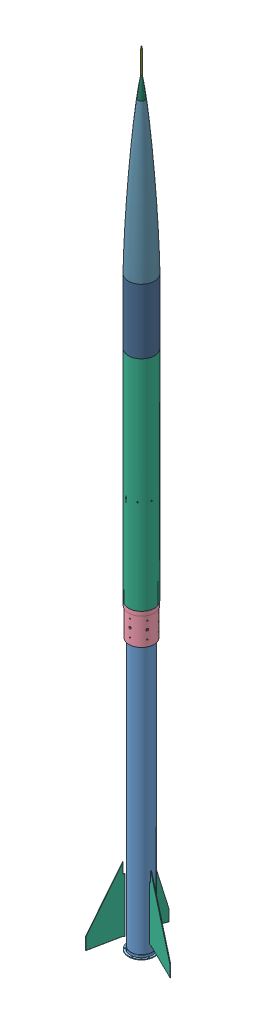
SolidWorks assembly NFPA_fullAssembly, configuration Default. Lengths in mm.
Overall size (305.82 3606.47 308.87).
264 component instances, 51 part files, 9 mates.
Components (placement in the parent):
- MotorAssembly-1: MotorAssembly [Default] at origin size (305.82 1521.25 308.87)
  - NFPAMotor-1: NFPAMotor [Default] at origin size (101.6 1308.35 101.6)
  - NFPA_ThrustPlate_MotorTube_V1-1: NFPA_ThrustPlate_MotorTube_V1 [Default] at (0 1295.654 0) x (0 1 0) z (-0.603474 0 0.797383) size (12 104.3 104.3)
  - 3014T471_STEEL EYEBOLT WITH SHOULDER - FOR LIFTING-1: 3014T471_STEEL EYEBOLT WITH SHOULDER - FOR LIFTING [3014T471] at (0 1337.9759 0) x (0.928789 0 0.37061) z (-0.37061 0 0.928789) size (42.07 88.72 17.46)
  - NFPA_MotorCoupler_MotorTube_V1-1: NFPA_MotorCoupler_MotorTube_V1 [Default] at (0 1231.454 0) x (0 -1 0) z (0.997437 0 -0.071547) size (273.05 119.3 119.3)
  - NFPA_CarbonTube_MotorTube_V1-1: NFPA_CarbonTube_MotorTube_V1 [Default] at (0 -10.7 0) x (0.97056 0 0.24086) z (-0.24086 0 0.97056) size (121.7 1369.15 121.7) (hidden)
  - NFPA_LowerRetainingStructure_MotorTube_V1-1: NFPA_LowerRetainingStructure_MotorTube_V1 [Default] at (0 -13.875 0) x (0.980838 0 -0.194827) z (0.194827 0 0.980838) size (118.62 3.17 118.62)
  - Fins-1: Fins [Default] at (1.2008 2699.2539 -1.2506) x (-0.276689 0 -0.96096) z (-0.96096 0 0.276689) size (128.37 356.05 3)
  - Fins-2: Fins [Default] at (-1.6835 2699.2539 -0.4147) x (-0.693871 0 0.7201) z (0.7201 0 0.693871) size (128.37 356.05 3)
  - Fins-3: Fins [Default] at (0.4826 2699.2539 1.6653) x (0.97056 0 0.24086) z (0.24086 0 -0.97056) size (128.37 356.05 3)
- NFPA_ASMPlusTube_AvionicsBay_V1-1: NFPA_ASMPlusTube_AvionicsBay_V1 [Default] at (4.3626 1788.1446 -124.7024) x (0.97858 0 0.205865) z (-0.205865 0 0.97858) size (169.53 1134.65 169.53)
  - NFPA_FinalAssembly_AvionicsBay_V1-1: NFPA_FinalAssembly_AvionicsBay_V1 [Default] at origin size (124.5 527 114.3)
    - NFPA_BottomBulkhead_AvionicsBay_V1-1: NFPA_BottomBulkhead_AvionicsBay_V1 [Default] at (21.4027 17.8594 122.9295) size (114.3 13 114.3)
    - NFPA_ThreadedRod_AvionicsBay_V1-1: NFPA_ThreadedRod_AvionicsBay_V1 [Default] at (-4.7602 2.8594 149.0924) size (6.35 475 6.35)
    - NFPA_ThreadedRod_AvionicsBay_V1-2: NFPA_ThreadedRod_AvionicsBay_V1 [Default] at (47.5656 2.8594 149.0924) size (6.35 475 6.35)
    - NFPA_ThreadedRod_AvionicsBay_V1-3: NFPA_ThreadedRod_AvionicsBay_V1 [Default] at (47.5656 2.8594 96.7664) size (6.35 475 6.35)
    - NFPA_ThreadedRod_AvionicsBay_V1-4: NFPA_ThreadedRod_AvionicsBay_V1 [Default] at (-4.7602 2.8594 96.7664) size (6.35 475 6.35)
    - 90107A029_TYPE 316 STAINLESS STEEL FLAT WASHER-1: 90107A029_TYPE 316 STAINLESS STEEL FLAT WASHER [90107A029] at (-4.7602 17.8594 96.7664) x (-0.837169 0 -0.546944) z (-0.546944 0 0.837169) size (15.88 1.09 15.88)
    - 90107A029_TYPE 316 STAINLESS STEEL FLAT WASHER-2: 90107A029_TYPE 316 STAINLESS STEEL FLAT WASHER [90107A029] at (-4.7602 17.8594 149.0924) x (-0.837169 0 -0.546944) z (-0.546944 0 0.837169) size (15.88 1.09 15.88)
    - 90107A029_TYPE 316 STAINLESS STEEL FLAT WASHER-3: 90107A029_TYPE 316 STAINLESS STEEL FLAT WASHER [90107A029] at (47.5656 17.8594 96.7664) x (-0.837169 0 -0.546944) z (-0.546944 0 0.837169) size (15.88 1.09 15.88)
    - 90107A029_TYPE 316 STAINLESS STEEL FLAT WASHER-4: 90107A029_TYPE 316 STAINLESS STEEL FLAT WASHER [90107A029] at (47.5656 17.8594 149.0924) x (-0.837169 0 -0.546944) z (-0.546944 0 0.837169) size (15.88 1.09 15.88)
    - 95462A029_GRADE 5 STEEL HEX NUT-1: 95462A029_GRADE 5 STEEL HEX NUT [95462A029] at (-4.7602 13.9891 149.0924) x (1 0 0) z (0 1 0) size (11.11 12.83 7.14)
    - 95462A029_GRADE 5 STEEL HEX NUT-2: 95462A029_GRADE 5 STEEL HEX NUT [95462A029] at (-4.7602 13.9891 96.7664) x (1 0 0) z (0 1 0) size (11.11 12.83 7.14)
    - 95462A029_GRADE 5 STEEL HEX NUT-3: 95462A029_GRADE 5 STEEL HEX NUT [95462A029] at (47.5656 13.9891 96.7664) x (1 0 0) z (0 1 0) size (11.11 12.83 7.14)
    - 95462A029_GRADE 5 STEEL HEX NUT-4: 95462A029_GRADE 5 STEEL HEX NUT [95462A029] at (47.5656 13.9891 149.0924) x (1 0 0) z (0 1 0) size (11.11 12.83 7.14)
    - NFPA_Raptor_AvionicsBay_V1-1: NFPA_Raptor_AvionicsBay_V1 [Default] at (51.4027 -12.9702 122.6596) x (0 1 0) z (-0.700909 0 0.71325) size (152.4 44.2 44.2)
    - 90107A029_TYPE 316 STAINLESS STEEL FLAT WASHER-5: 90107A029_TYPE 316 STAINLESS STEEL FLAT WASHER [90107A029] at (47.5656 56.1811 149.0924) x (-0.837169 0 -0.546944) z (-0.546944 0 0.837169) size (15.88 1.09 15.88)
    - 90107A029_TYPE 316 STAINLESS STEEL FLAT WASHER-6: 90107A029_TYPE 316 STAINLESS STEEL FLAT WASHER [90107A029] at (-4.7602 56.4993 149.0924) x (-0.797616 0 -0.603165) z (-0.603165 0 0.797616) size (15.88 1.09 15.88)
    - 90107A029_TYPE 316 STAINLESS STEEL FLAT WASHER-7: 90107A029_TYPE 316 STAINLESS STEEL FLAT WASHER [90107A029] at (47.5656 58.7462 149.0924) x (-0.771468 0 -0.636268) z (-0.636268 0 0.771468) size (15.88 1.09 15.88)
    - 90107A029_TYPE 316 STAINLESS STEEL FLAT WASHER-8: 90107A029_TYPE 316 STAINLESS STEEL FLAT WASHER [90107A029] at (-4.7602 59.0072 149.0924) x (-0.839969 0 -0.542635) z (-0.542635 0 0.839969) size (15.88 1.09 15.88)
    - 90107A029_TYPE 316 STAINLESS STEEL FLAT WASHER-9: 90107A029_TYPE 316 STAINLESS STEEL FLAT WASHER [90107A029] at (47.5656 58.8468 96.7664) x (-0.837169 0 -0.546944) z (-0.546944 0 0.837169) size (15.88 1.09 15.88)
    - 90107A029_TYPE 316 STAINLESS STEEL FLAT WASHER-10: 90107A029_TYPE 316 STAINLESS STEEL FLAT WASHER [90107A029] at (-4.7602 58.9433 96.7664) x (-0.782663 0 -0.622446) z (-0.622446 0 0.782663) size (15.88 1.09 15.88)
    - 90107A029_TYPE 316 STAINLESS STEEL FLAT WASHER-11: 90107A029_TYPE 316 STAINLESS STEEL FLAT WASHER [90107A029] at (-4.7602 56.1457 96.7664) x (-0.837169 0 -0.546944) z (-0.546944 0 0.837169) size (15.88 1.09 15.88)
    - 90107A029_TYPE 316 STAINLESS STEEL FLAT WASHER-12: 90107A029_TYPE 316 STAINLESS STEEL FLAT WASHER [90107A029] at (47.5656 56.204 96.7664) x (-0.837169 0 -0.546944) z (-0.546944 0 0.837169) size (15.88 1.09 15.88)
    - 95462A029_GRADE 5 STEEL HEX NUT-5: 95462A029_GRADE 5 STEEL HEX NUT [95462A029] at (-4.7602 52.2753 96.7664) x (0.99903 0 0.044034) z (0 -1 0) size (11.11 12.83 7.14)
    - 95462A029_GRADE 5 STEEL HEX NUT-6: 95462A029_GRADE 5 STEEL HEX NUT [95462A029] at (47.5656 52.3337 96.7664) x (0.997972 0 0.063657) z (0 1 0) size (11.11 12.83 7.14)
    - 95462A029_GRADE 5 STEEL HEX NUT-7: 95462A029_GRADE 5 STEEL HEX NUT [95462A029] at (47.5656 61.6249 96.7664) x (0.988116 0 -0.153711) z (0 1 0) size (11.11 12.83 7.14)
    - 95462A029_GRADE 5 STEEL HEX NUT-8: 95462A029_GRADE 5 STEEL HEX NUT [95462A029] at (-4.7602 61.7214 96.7664) x (1 0 0) z (0 1 0) size (11.11 12.83 7.14)
    - 95462A029_GRADE 5 STEEL HEX NUT-9: 95462A029_GRADE 5 STEEL HEX NUT [95462A029] at (47.5656 61.5243 149.0924) x (1 0 0) z (0 1 0) size (11.11 12.83 7.14)
    - 95462A029_GRADE 5 STEEL HEX NUT-10: 95462A029_GRADE 5 STEEL HEX NUT [95462A029] at (-4.7602 61.7853 149.0924) x (0.99999 0 -0.004368) z (0 1 0) size (11.11 12.83 7.14)
    - 95462A029_GRADE 5 STEEL HEX NUT-11: 95462A029_GRADE 5 STEEL HEX NUT [95462A029] at (-4.7602 52.629 149.0924) x (1 0 0) z (0 -1 0) size (11.11 12.83 7.14)
    - 95462A029_GRADE 5 STEEL HEX NUT-12: 95462A029_GRADE 5 STEEL HEX NUT [95462A029] at (47.5656 52.3108 149.0924) x (0.985546 0 -0.169407) z (0 -1 0) size (11.11 12.83 7.14)
    - NFPA_TopBulkhead_AvionicsBay_V1-1: NFPA_TopBulkhead_AvionicsBay_V1 [Default] at (21.4027 430.8586 122.9293) x (-1 0 0) z (0 0 -1) size (114.3 13 114.3)
    - 90107A029_TYPE 316 STAINLESS STEEL FLAT WASHER-13: 90107A029_TYPE 316 STAINLESS STEEL FLAT WASHER [90107A029] at (-4.7602 444.9508 149.0924) x (-0.837169 0 -0.546944) z (-0.546944 0 0.837169) size (15.88 1.09 15.88)
    - 90107A029_TYPE 316 STAINLESS STEEL FLAT WASHER-14: 90107A029_TYPE 316 STAINLESS STEEL FLAT WASHER [90107A029] at (47.5656 444.9508 149.0924) x (-0.837169 0 -0.546944) z (-0.546944 0 0.837169) size (15.88 1.09 15.88)
    - 90107A029_TYPE 316 STAINLESS STEEL FLAT WASHER-15: 90107A029_TYPE 316 STAINLESS STEEL FLAT WASHER [90107A029] at (-4.7602 444.9508 96.7664) x (-0.837169 0 -0.546944) z (-0.546944 0 0.837169) size (15.88 1.09 15.88)
    - 90107A029_TYPE 316 STAINLESS STEEL FLAT WASHER-16: 90107A029_TYPE 316 STAINLESS STEEL FLAT WASHER [90107A029] at (47.5656 444.9508 96.7664) x (-0.837169 0 -0.546944) z (-0.546944 0 0.837169) size (15.88 1.09 15.88)
    - 95462A029_GRADE 5 STEEL HEX NUT-13: 95462A029_GRADE 5 STEEL HEX NUT [95462A029] at (47.5656 447.7289 149.0924) x (1 0 0) z (0 1 0) size (11.11 12.83 7.14)
    - 95462A029_GRADE 5 STEEL HEX NUT-14: 95462A029_GRADE 5 STEEL HEX NUT [95462A029] at (-4.7602 447.7289 149.0924) x (1 0 0) z (0 1 0) size (11.11 12.83 7.14)
    - 95462A029_GRADE 5 STEEL HEX NUT-15: 95462A029_GRADE 5 STEEL HEX NUT [95462A029] at (-4.7602 447.7289 96.7664) x (1 0 0) z (0 -1 0) size (11.11 12.83 7.14)
    - 95462A029_GRADE 5 STEEL HEX NUT-16: 95462A029_GRADE 5 STEEL HEX NUT [95462A029] at (47.5656 447.7289 96.7664) x (1 0 0) z (0 -1 0) size (11.11 12.83 7.14)
    - NFPA_Raptor_AvionicsBay_V1-2: NFPA_Raptor_AvionicsBay_V1 [Default] at (-10.5973 474.6883 122.9293) x (0 -1 0) z (0.694658 0 0.71934) size (152.4 44.2 44.2)
    - NFPA_GeneralPCB_AvionicsBay_V1-2: NFPA_GeneralPCB_AvionicsBay_V1 [Default] at (21.4026 125.3758 122.9294) x (1 0 -0.000004) z (0.000004 0 1) size (75 1.6 75)
    - NFPA_GeneralPCB_AvionicsBay_V1-3: NFPA_GeneralPCB_AvionicsBay_V1 [Default] at (21.4025 146.9758 122.9295) size (75 1.6 75)
    - NFPA_GeneralPCB_AvionicsBay_V1-4: NFPA_GeneralPCB_AvionicsBay_V1 [Default] at (21.4027 168.5758 122.9295) size (75 1.6 75)
    - NFPA_GeneralPCB_AvionicsBay_V1-5: NFPA_GeneralPCB_AvionicsBay_V1 [Default] at (21.4027 211.7758 122.9295) size (75 1.6 75)
    - NFPA_GeneralPCB_AvionicsBay_V1-6: NFPA_GeneralPCB_AvionicsBay_V1 [Default] at (21.4025 190.1758 122.9295) size (75 1.6 75)
    - NFPA_GeneralPCB_AvionicsBay_V1-7: NFPA_GeneralPCB_AvionicsBay_V1 [Default] at (21.4026 233.3758 122.9294) x (1 0 0.000004) z (-0.000004 0 1) size (75 1.6 75)
    - NFPA_GeneralPCB_AvionicsBay_V1-8: NFPA_GeneralPCB_AvionicsBay_V1 [Default] at (21.4025 254.9758 122.9295) size (75 1.6 75)
    - NFPA_GeneralPCB_AvionicsBay_V1-9: NFPA_GeneralPCB_AvionicsBay_V1 [Default] at (21.4025 276.5758 122.9295) size (75 1.6 75)
    - 90107A029_TYPE 316 STAINLESS STEEL FLAT WASHER-17: 90107A029_TYPE 316 STAINLESS STEEL FLAT WASHER [90107A029] at (-4.7602 125.3758 96.7664) x (-0.837169 0 -0.546944) z (-0.546944 0 0.837169) size (15.88 1.09 15.88)
    - 90107A029_TYPE 316 STAINLESS STEEL FLAT WASHER-18: 90107A029_TYPE 316 STAINLESS STEEL FLAT WASHER [90107A029] at (-4.7602 125.3758 149.0924) x (-0.837169 0 -0.546944) z (-0.546944 0 0.837169) size (15.88 1.09 15.88)
    - 90107A029_TYPE 316 STAINLESS STEEL FLAT WASHER-19: 90107A029_TYPE 316 STAINLESS STEEL FLAT WASHER [90107A029] at (47.5656 125.3758 96.7664) x (-0.837169 0 -0.546944) z (-0.546944 0 0.837169) size (15.88 1.09 15.88)
    - 90107A029_TYPE 316 STAINLESS STEEL FLAT WASHER-20: 90107A029_TYPE 316 STAINLESS STEEL FLAT WASHER [90107A029] at (47.5656 125.3758 149.0924) x (-0.837169 0 -0.546944) z (-0.546944 0 0.837169) size (15.88 1.09 15.88)
    - 95462A029_GRADE 5 STEEL HEX NUT-17: 95462A029_GRADE 5 STEEL HEX NUT [95462A029] at (-4.7602 121.5054 96.7664) x (1 0 0) z (0 1 0) size (11.11 12.83 7.14)
    - 95462A029_GRADE 5 STEEL HEX NUT-18: 95462A029_GRADE 5 STEEL HEX NUT [95462A029] at (-4.7602 121.5054 149.0924) x (1 0 0) z (0 1 0) size (11.11 12.83 7.14)
    - 95462A029_GRADE 5 STEEL HEX NUT-19: 95462A029_GRADE 5 STEEL HEX NUT [95462A029] at (47.5656 121.5054 149.0924) x (1 0 0) z (0 1 0) size (11.11 12.83 7.14)
    - 95462A029_GRADE 5 STEEL HEX NUT-20: 95462A029_GRADE 5 STEEL HEX NUT [95462A029] at (47.5656 121.5054 96.7664) x (1 0 0) z (0 1 0) size (11.11 12.83 7.14)
    - NFPA_PCBSpacer_AvionicsBay_V1-1: NFPA_PCBSpacer_AvionicsBay_V1 [Default] at (-4.7604 126.9758 149.0924) size (14.5 30 14.5)
    - NFPA_PCBSpacer_AvionicsBay_V1-2: NFPA_PCBSpacer_AvionicsBay_V1 [Default] at (47.5656 126.9758 149.0924) size (14.5 30 14.5)
    - NFPA_PCBSpacer_AvionicsBay_V1-3: NFPA_PCBSpacer_AvionicsBay_V1 [Default] at (47.5656 126.9758 96.7666) size (14.5 30 14.5)
    - NFPA_PCBSpacer_AvionicsBay_V1-4: NFPA_PCBSpacer_AvionicsBay_V1 [Default] at (-4.7604 126.9758 96.7666) size (14.5 30 14.5)
    - NFPA_PCBSpacer_AvionicsBay_V1-5: NFPA_PCBSpacer_AvionicsBay_V1 [Default] at (-4.7602 148.5758 96.7666) size (14.5 30 14.5)
    - NFPA_PCBSpacer_AvionicsBay_V1-6: NFPA_PCBSpacer_AvionicsBay_V1 [Default] at (-4.7604 170.1758 149.0924) size (14.5 30 14.5)
    - NFPA_PCBSpacer_AvionicsBay_V1-7: NFPA_PCBSpacer_AvionicsBay_V1 [Default] at (-4.7604 170.1758 96.7666) size (14.5 30 14.5)
    - NFPA_PCBSpacer_AvionicsBay_V1-8: NFPA_PCBSpacer_AvionicsBay_V1 [Default] at (47.5656 170.1758 149.0924) size (14.5 30 14.5)
    - NFPA_PCBSpacer_AvionicsBay_V1-9: NFPA_PCBSpacer_AvionicsBay_V1 [Default] at (-4.7602 148.5758 149.0924) size (14.5 30 14.5)
    - NFPA_PCBSpacer_AvionicsBay_V1-10: NFPA_PCBSpacer_AvionicsBay_V1 [Default] at (47.5658 148.5758 149.0924) size (14.5 30 14.5)
    - NFPA_PCBSpacer_AvionicsBay_V1-11: NFPA_PCBSpacer_AvionicsBay_V1 [Default] at (47.5658 148.5758 96.7666) size (14.5 30 14.5)
    - NFPA_PCBSpacer_AvionicsBay_V1-12: NFPA_PCBSpacer_AvionicsBay_V1 [Default] at (47.5656 170.1758 96.7666) size (14.5 30 14.5)
    - NFPA_PCBSpacer_AvionicsBay_V1-13: NFPA_PCBSpacer_AvionicsBay_V1 [Default] at (47.5658 191.7758 149.0924) size (14.5 30 14.5)
    - NFPA_PCBSpacer_AvionicsBay_V1-14: NFPA_PCBSpacer_AvionicsBay_V1 [Default] at (47.5658 191.7758 96.7666) size (14.5 30 14.5)
    - NFPA_PCBSpacer_AvionicsBay_V1-15: NFPA_PCBSpacer_AvionicsBay_V1 [Default] at (-4.7602 191.7758 149.0924) size (14.5 30 14.5)
    - NFPA_PCBSpacer_AvionicsBay_V1-16: NFPA_PCBSpacer_AvionicsBay_V1 [Default] at (-4.7602 191.7758 96.7666) size (14.5 30 14.5)
    - NFPA_PCBSpacer_AvionicsBay_V1-17: NFPA_PCBSpacer_AvionicsBay_V1 [Default] at (-4.7602 213.3758 96.7664) size (14.5 30 14.5)
    - NFPA_PCBSpacer_AvionicsBay_V1-18: NFPA_PCBSpacer_AvionicsBay_V1 [Default] at (47.5658 213.3758 96.7666) size (14.5 30 14.5)
    - NFPA_PCBSpacer_AvionicsBay_V1-19: NFPA_PCBSpacer_AvionicsBay_V1 [Default] at (-4.7604 213.3758 149.0922) size (14.5 30 14.5)
    - NFPA_PCBSpacer_AvionicsBay_V1-20: NFPA_PCBSpacer_AvionicsBay_V1 [Default] at (47.5656 213.3758 149.0924) size (14.5 30 14.5)
    - NFPA_PCBSpacer_AvionicsBay_V1-21: NFPA_PCBSpacer_AvionicsBay_V1 [Default] at (-4.7604 234.9758 149.0924) size (14.5 30 14.5)
    - NFPA_PCBSpacer_AvionicsBay_V1-22: NFPA_PCBSpacer_AvionicsBay_V1 [Default] at (-4.7604 234.9758 96.7666) size (14.5 30 14.5)
    - NFPA_PCBSpacer_AvionicsBay_V1-23: NFPA_PCBSpacer_AvionicsBay_V1 [Default] at (47.5656 234.9758 96.7666) size (14.5 30 14.5)
    - NFPA_PCBSpacer_AvionicsBay_V1-24: NFPA_PCBSpacer_AvionicsBay_V1 [Default] at (47.5656 234.9758 149.0924) size (14.5 30 14.5)
    - NFPA_PCBSpacer_AvionicsBay_V1-25: NFPA_PCBSpacer_AvionicsBay_V1 [Default] at (-4.7604 256.5758 96.7666) size (14.5 30 14.5)
    - NFPA_PCBSpacer_AvionicsBay_V1-26: NFPA_PCBSpacer_AvionicsBay_V1 [Default] at (-4.7604 256.5758 149.0924) size (14.5 30 14.5)
    - NFPA_PCBSpacer_AvionicsBay_V1-27: NFPA_PCBSpacer_AvionicsBay_V1 [Default] at (47.5656 256.5758 96.7666) size (14.5 30 14.5)
    - NFPA_PCBSpacer_AvionicsBay_V1-28: NFPA_PCBSpacer_AvionicsBay_V1 [Default] at (47.5656 256.5758 149.0924) size (14.5 30 14.5)
    - 90107A029_TYPE 316 STAINLESS STEEL FLAT WASHER-21: 90107A029_TYPE 316 STAINLESS STEEL FLAT WASHER [90107A029] at (-4.7602 292.268 96.7664) x (-0.832281 0 -0.554354) z (-0.554354 0 0.832281) size (15.88 1.09 15.88)
    - 90107A029_TYPE 316 STAINLESS STEEL FLAT WASHER-22: 90107A029_TYPE 316 STAINLESS STEEL FLAT WASHER [90107A029] at (-4.7602 292.268 149.0924) x (-0.837169 0 -0.546944) z (-0.546944 0 0.837169) size (15.88 1.09 15.88)
    - 90107A029_TYPE 316 STAINLESS STEEL FLAT WASHER-23: 90107A029_TYPE 316 STAINLESS STEEL FLAT WASHER [90107A029] at (47.5656 292.268 96.7664) x (-0.837169 0 -0.546944) z (-0.546944 0 0.837169) size (15.88 1.09 15.88)
    - 90107A029_TYPE 316 STAINLESS STEEL FLAT WASHER-24: 90107A029_TYPE 316 STAINLESS STEEL FLAT WASHER [90107A029] at (47.5656 292.268 149.0924) x (-0.837169 0 -0.546944) z (-0.546944 0 0.837169) size (15.88 1.09 15.88)
    - 95462A029_GRADE 5 STEEL HEX NUT-21: 95462A029_GRADE 5 STEEL HEX NUT [95462A029] at (-4.7602 295.0461 96.7664) x (0.995655 0 0.093122) z (0 -1 0) size (11.11 12.83 7.14)
    - 95462A029_GRADE 5 STEEL HEX NUT-22: 95462A029_GRADE 5 STEEL HEX NUT [95462A029] at (47.5656 295.0461 149.0924) x (0.989679 0 -0.143305) z (0 -1 0) size (11.11 12.83 7.14)
    - 95462A029_GRADE 5 STEEL HEX NUT-23: 95462A029_GRADE 5 STEEL HEX NUT [95462A029] at (47.5656 295.0461 96.7664) x (0.995114 0 -0.098732) z (0 -1 0) size (11.11 12.83 7.14)
    - 95462A029_GRADE 5 STEEL HEX NUT-24: 95462A029_GRADE 5 STEEL HEX NUT [95462A029] at (-4.7602 295.0461 149.0924) x (0.96356 0 -0.267493) z (0 -1 0) size (11.11 12.83 7.14)
    - HolderAsn-1: HolderAsn [Default] at (38.9027 61.7811 138.4295) x (0 0 -1) z (1 0 0) size (94.18 67.6 82.09)
      - HolderBlock-1: HolderBlock [Default] at origin size (50 66 50)
      - bx0033-1: bx0033 [Default] at (31.6 1.93 -15) x (0 0 1) z (0 1 0) size (29.85 36.83 58.82)
        - bx0033_01-1: bx0033_01 [Default] at origin size (29.85 30.4 58.82)
        - bx0033_02-1: bx0033_02 [Default] at origin size (9.53 36.83 6.65)
        - bx0033_03-1: bx0033_03 [Default] at origin size (9.53 36.83 6.65)
      - bx0033-2: bx0033 [Default] at (-1.6 1.93 -15) x (0 0 -1) z (0 1 0) size (29.85 36.83 58.82)
        - bx0033_01-1: bx0033_01 [Default] at origin size (29.85 30.4 58.82)
        - bx0033_02-1: bx0033_02 [Default] at origin size (9.53 36.83 6.65)
        - bx0033_03-1: bx0033_03 [Default] at origin size (9.53 36.83 6.65)
      - BatteryHolder_M3-1: BatteryHolder_M3 [92125A103] at (-6.76 14 -15) x (0 0.924225 0.381849) z (-1 0 0) size (6 6 15.33)
      - BatteryHolder_M3-2: BatteryHolder_M3 [92125A103] at (36.76 14 -15) x (0 0 -1) z (1 0 0) size (6 6 15.33)
      - BatteryHolder_M3-3: BatteryHolder_M3 [92125A103] at (36.76 27.97 -15) x (0 -0.980885 0.19459) z (1 0 0) size (6 6 15.33)
      - BatteryHolder_M3-4: BatteryHolder_M3 [92125A103] at (-6.76 27.97 -15) x (0 0.567416 -0.823431) z (-1 0 0) size (6 6 15.33)
      - bx0033-3: bx0033 [Default] at (15 1.93 -31.6) x (1 0 0) z (0 1 0) size (29.85 36.83 58.82)
        - bx0033_01-1: bx0033_01 [Default] at origin size (29.85 30.4 58.82)
        - bx0033_02-1: bx0033_02 [Default] at origin size (9.53 36.83 6.65)
        - bx0033_03-1: bx0033_03 [Default] at origin size (9.53 36.83 6.65)
      - BatteryHolder_M3-5: BatteryHolder_M3 [92125A103] at (15 14 -36.735) x (-1 0 0) z (0 0 -1) size (6 6 15.33)
      - BatteryHolder_M3-6: BatteryHolder_M3 [92125A103] at (15 27.97 -36.735) x (-1 0 0) z (0 0 -1) size (6 6 15.33)
      - NFPA_BatteryPCB_AvionicsBay_V1-1: NFPA_BatteryPCB_AvionicsBay_V1 [Default] at (15.5 -5.6 -17.5) size (75 1.6 75)
    - NFPA_2BatteryHolder_AvionicsBay_V1-2: NFPA_2BatteryHolder_AvionicsBay_V1 [Default] at (28.8268 322.7405 142.5263) size (39.78 21.54 77.06)
    - NFPA_GeneralPCB_AvionicsBay_V1-10: NFPA_GeneralPCB_AvionicsBay_V1 [Default] at (21.4026 321.1405 122.9294) x (1 0 0.000004) z (-0.000004 0 1) size (75 1.6 75)
    - NFPA_GeneralPCB_AvionicsBay_V1-11: NFPA_GeneralPCB_AvionicsBay_V1 [Default] at (21.4026 348.7405 122.9294) x (1 0 -0.000004) z (0.000004 0 1) size (75 1.6 75)
    - NFPA_GeneralPCB_AvionicsBay_V1-12: NFPA_GeneralPCB_AvionicsBay_V1 [Default] at (21.4026 376.3405 122.9294) x (1 0 -0.000004) z (0.000004 0 1) size (75 1.6 75)
    - 90107A029_TYPE 316 STAINLESS STEEL FLAT WASHER-25: 90107A029_TYPE 316 STAINLESS STEEL FLAT WASHER [90107A029] at (-4.7602 320.0483 96.7664) size (15.88 1.09 15.88)
    - 90107A029_TYPE 316 STAINLESS STEEL FLAT WASHER-26: 90107A029_TYPE 316 STAINLESS STEEL FLAT WASHER [90107A029] at (47.5656 320.0483 96.7664) size (15.88 1.09 15.88)
    - 90107A029_TYPE 316 STAINLESS STEEL FLAT WASHER-27: 90107A029_TYPE 316 STAINLESS STEEL FLAT WASHER [90107A029] at (47.5656 320.0483 149.0924) size (15.88 1.09 15.88)
    - 90107A029_TYPE 316 STAINLESS STEEL FLAT WASHER-28: 90107A029_TYPE 316 STAINLESS STEEL FLAT WASHER [90107A029] at (-4.7602 320.0483 149.0924) size (15.88 1.09 15.88)
    - 95462A029_GRADE 5 STEEL HEX NUT-25: 95462A029_GRADE 5 STEEL HEX NUT [95462A029] at (47.5656 317.2701 149.0924) x (1 0 0) z (0 1 0) size (11.11 12.83 7.14)
    - 95462A029_GRADE 5 STEEL HEX NUT-26: 95462A029_GRADE 5 STEEL HEX NUT [95462A029] at (-4.7602 317.2701 96.7664) x (1 0 0) z (0 1 0) size (11.11 12.83 7.14)
    - 95462A029_GRADE 5 STEEL HEX NUT-27: 95462A029_GRADE 5 STEEL HEX NUT [95462A029] at (47.5656 317.2701 96.7664) x (1 0 0) z (0 1 0) size (11.11 12.83 7.14)
    - 95462A029_GRADE 5 STEEL HEX NUT-28: 95462A029_GRADE 5 STEEL HEX NUT [95462A029] at (-4.7602 317.2701 149.0924) x (1 0 0) z (0 1 0) size (11.11 12.83 7.14)
    - NFPA_BatteryPCBSpacer_AvionicsBay_V1-1: NFPA_BatteryPCBSpacer_AvionicsBay_V1 [Default] at (47.5656 322.7405 149.0924) size (12.5 35 12.5)
    - NFPA_BatteryPCBSpacer_AvionicsBay_V1-2: NFPA_BatteryPCBSpacer_AvionicsBay_V1 [Default] at (-4.7602 322.7405 149.0924) size (12.5 35 12.5)
    - NFPA_BatteryPCBSpacer_AvionicsBay_V1-3: NFPA_BatteryPCBSpacer_AvionicsBay_V1 [Default] at (47.5656 322.7405 96.7664) size (12.5 35 12.5)
    - NFPA_BatteryPCBSpacer_AvionicsBay_V1-4: NFPA_BatteryPCBSpacer_AvionicsBay_V1 [Default] at (-4.7602 322.7405 96.7664) size (12.5 35 12.5)
    - NFPA_BatteryPCBSpacer_AvionicsBay_V1-5: NFPA_BatteryPCBSpacer_AvionicsBay_V1 [Default] at (47.5656 350.3405 96.7664) x (0.961213 0 -0.275806) z (0.275806 0 0.961213) size (12.5 35 12.5)
    - NFPA_BatteryPCBSpacer_AvionicsBay_V1-6: NFPA_BatteryPCBSpacer_AvionicsBay_V1 [Default] at (47.5656 350.3405 149.0924) size (12.5 35 12.5)
    - NFPA_BatteryPCBSpacer_AvionicsBay_V1-7: NFPA_BatteryPCBSpacer_AvionicsBay_V1 [Default] at (-4.7602 350.3405 96.7664) size (12.5 35 12.5)
    - NFPA_BatteryPCBSpacer_AvionicsBay_V1-8: NFPA_BatteryPCBSpacer_AvionicsBay_V1 [Default] at (-4.7602 350.3405 149.0924) size (12.5 35 12.5)
    - NFPA_2BatteryHolder_AvionicsBay_V1-3: NFPA_2BatteryHolder_AvionicsBay_V1 [Default] at (28.8058 377.9405 142.5871) size (39.78 21.54 77.06)
    - NFPA_2BatteryHolder_AvionicsBay_V1-4: NFPA_2BatteryHolder_AvionicsBay_V1 [Default] at (28.6573 350.3405 142.6856) size (39.78 21.54 77.06)
    - NFPA_BatteryPCBSpacer_AvionicsBay_V1-10: NFPA_BatteryPCBSpacer_AvionicsBay_V1 [Default] at (-4.7602 377.9405 149.0924) size (12.5 35 12.5)
    - NFPA_BatteryPCBSpacer_AvionicsBay_V1-11: NFPA_BatteryPCBSpacer_AvionicsBay_V1 [Default] at (-4.7602 377.9405 96.7664) size (12.5 35 12.5)
    - NFPA_BatteryPCBSpacer_AvionicsBay_V1-12: NFPA_BatteryPCBSpacer_AvionicsBay_V1 [Default] at (47.5656 377.9405 149.0924) size (12.5 35 12.5)
    - NFPA_BatteryPCBSpacer_AvionicsBay_V1-13: NFPA_BatteryPCBSpacer_AvionicsBay_V1 [Default] at (47.5656 377.9405 96.7664) size (12.5 35 12.5)
    - 90107A029_TYPE 316 STAINLESS STEEL FLAT WASHER-30: 90107A029_TYPE 316 STAINLESS STEEL FLAT WASHER [90107A029] at (-4.7602 412.9405 96.7664) size (15.88 1.09 15.88)
    - 90107A029_TYPE 316 STAINLESS STEEL FLAT WASHER-31: 90107A029_TYPE 316 STAINLESS STEEL FLAT WASHER [90107A029] at (47.5656 412.9405 96.7664) size (15.88 1.09 15.88)
    - 90107A029_TYPE 316 STAINLESS STEEL FLAT WASHER-32: 90107A029_TYPE 316 STAINLESS STEEL FLAT WASHER [90107A029] at (-4.7602 412.9405 149.0924) size (15.88 1.09 15.88)
    - 90107A029_TYPE 316 STAINLESS STEEL FLAT WASHER-33: 90107A029_TYPE 316 STAINLESS STEEL FLAT WASHER [90107A029] at (47.5656 412.9405 149.0924) size (15.88 1.09 15.88)
    - 95462A029_GRADE 5 STEEL HEX NUT-29: 95462A029_GRADE 5 STEEL HEX NUT [95462A029] at (47.5656 416.8108 149.0924) x (1 0 0) z (0 -1 0) size (11.11 12.83 7.14)
    - 95462A029_GRADE 5 STEEL HEX NUT-30: 95462A029_GRADE 5 STEEL HEX NUT [95462A029] at (-4.7602 416.8108 96.7664) x (1 0 0) z (0 -1 0) size (11.11 12.83 7.14)
    - 95462A029_GRADE 5 STEEL HEX NUT-31: 95462A029_GRADE 5 STEEL HEX NUT [95462A029] at (-4.7602 416.8108 149.0924) x (1 0 0) z (0 -1 0) size (11.11 12.83 7.14)
    - 95462A029_GRADE 5 STEEL HEX NUT-32: 95462A029_GRADE 5 STEEL HEX NUT [95462A029] at (47.5656 416.8108 96.7664) x (1 0 0) z (0 -1 0) size (11.11 12.83 7.14)
    - NFPA_SpacerCap_AvionicsBay_V1-1: NFPA_SpacerCap_AvionicsBay_V1 [Default] at (47.5656 278.1758 149.0924) size (14.5 13 14.5)
    - NFPA_SpacerCap_AvionicsBay_V1-2: NFPA_SpacerCap_AvionicsBay_V1 [Default] at (47.5656 278.1758 96.7664) size (14.5 13 14.5)
    - NFPA_SpacerCap_AvionicsBay_V1-3: NFPA_SpacerCap_AvionicsBay_V1 [Default] at (-4.7602 278.1758 96.7664) size (14.5 13 14.5)
    - NFPA_SpacerCap_AvionicsBay_V1-4: NFPA_SpacerCap_AvionicsBay_V1 [Default] at (-4.7602 278.1758 149.0924) size (14.5 13 14.5)
  - Avi_Para_tube-2: Avi_Para_tube [Default] at (21.4027 -1649.5513 122.9295) x (0 -1 0) z (-0.707107 0 0.707107) size (1134.65 119.87 119.87)
  - Num4ScrewLowerAviBulkhead-1: Num4ScrewLowerAviBulkhead [92220A122] at (21.4027 24.3594 178.1033) x (0 0 -1) z (0.810068 -0.586337 0) size (11.33 4.65 4.65)
  - Num4ScrewLowerAviBulkhead-2: Num4ScrewLowerAviBulkhead [92220A122] at (60.4165 24.3594 161.9433) x (-0.707107 0 -0.707107) z (0.572804 -0.586337 -0.572804) size (11.33 4.65 4.65)
  - Num4ScrewLowerAviBulkhead-3: Num4ScrewLowerAviBulkhead [92220A122] at (76.5766 24.3594 122.9295) x (-1 0 0) z (0 -0.586337 -0.810068) size (11.33 4.65 4.65)
  - Num4ScrewLowerAviBulkhead-4: Num4ScrewLowerAviBulkhead [92220A122] at (60.4165 24.3594 83.9156) x (-0.707107 0 0.707107) z (-0.572804 -0.586337 -0.572804) size (11.33 4.65 4.65)
  - Num4ScrewLowerAviBulkhead-5: Num4ScrewLowerAviBulkhead [92220A122] at (21.4027 24.3594 67.7556) x (0 0 1) z (-0.810068 -0.586337 0) size (11.33 4.65 4.65)
  - Num4ScrewLowerAviBulkhead-6: Num4ScrewLowerAviBulkhead [92220A122] at (-17.6111 24.3594 83.9156) x (0.707107 0 0.707107) z (-0.572804 -0.586337 0.572804) size (11.33 4.65 4.65)
  - Num4ScrewLowerAviBulkhead-7: Num4ScrewLowerAviBulkhead [92220A122] at (-33.7712 24.3594 122.9295) x (1 0 0) z (0 -0.586337 0.810068) size (11.33 4.65 4.65)
  - Num4ScrewLowerAviBulkhead-8: Num4ScrewLowerAviBulkhead [92220A122] at (-17.6111 24.3594 161.9433) x (0.707107 0 -0.707107) z (0.572804 -0.586337 0.572804) size (11.33 4.65 4.65)
  - main_Chute-1: main_Chute [Default] at (21.4027 -410.6406 122.9295) x (0.99733 0 0.073026) z (-0.073026 0 0.99733) size (100 275 100)
  - drogue_Chute-1: drogue_Chute [Default] at (21.4027 -36.6406 122.9295) x (-0.831378 0 -0.555707) z (0 -1 0) size (50.8 50.8 99)
- Payload_tube-1: Payload_tube [Default] at (0 2385.1499 0) x (0.989967 0 0.141298) z (-0.141298 0 0.989967) size (119.88 297.6 119.88)
- NFPA_Payload_asm_V1-1: NFPA_Payload_asm_V1 [Default] at (0 2769.2632 0) x (0.390584 0 -0.920567) z (-0.920567 0 -0.390584) size (153.53 555.01 153.53)
  - Glider lid-1: Glider lid [Default] at origin size (101.6 29.56 103.58)
  - PayloadBay-1: PayloadBay [Default] at (0 460.375 0) x (-0.837169 0 -0.546944) z (-0.546944 0 0.837169) size (101.6 555.01 101.6)
  - retaining ring-1: retaining ring [Default] at (0.015 2.1084 0.013) x (0.826256 0 0.563295) z (-0.563295 0 0.826256) size (110.49 12.7 110.49)
- NoseconeAsm-1: NoseconeAsm [Default] at (-226.7218 2521.6293 -645.7586) size (98.34 454.25 98.34)
  - noseCone-1: noseCone [Default] at (226.7218 161.1206 645.7586) x (-1 0 0) z (0 0 1) size (120 813.97 120)
  - NOSECONE_TIP-1: NOSECONE_TIP [Default] at (226.717 961.2789 645.6249) x (0 -1 0) z (0.999354 0 -0.035938) size (105.75 31.88 31.88)
  - PTube-1: PTube [Default] at (226.717 843.0906 645.6249) x (0.614963 0 0.788556) z (-0.788556 0 0.614963) size (5.11 225 5.11)
  - PCB_retainer_Asm-1: PCB_retainer_Asm [Default] at (226.7218 629.513 645.7586) size (98.34 18.34 98.34)
    - Retaining plate-1: Retaining plate [Default] at origin size (70.03 2 70.03)
    - BansheePCB-1: BansheePCB [Default] at (49.813 -10.6 179.2168) x (-0.785717 0 -0.618586) z (0 1 0) size (70.03 70.03 10.55)
      - PT0.step-1: PT0.step [Default] at origin size (70.03 70.03 10.55)
        - PinHeader_2x05_P1.27mm_Vertical.step-1: PinHeader_2x05_P1.27mm_Vertical.step [Default] at (148.25 -130.23 -0.05) x (1 0 0) z (0 0 -1) size (3.4 6.35 6.3)
          - SOLID.step-1: SOLID.step [Default] at origin size (3.4 6.35 6.3)
        - SOT-23.step-1: SOT-23.step [Default] at (138 -129 1.65) size (2.5 3 1.2)
          - SOLID-0.step-1: SOLID-0.step [Default] at origin size (2.5 3 1.2)
        - SOT-23.step-2: SOT-23.step [Default] at (138 -124 1.65) size (2.5 3 1.2)
          - SOLID-0.step-1: SOLID-0.step [Default] at origin size (2.5 3 1.2)
        - R_0805_2012Metric.step-1: R_0805_2012Metric.step [Default] at (177.975 -120 1.65) size (2 1.2 0.45)
          - SOLID-1.step-1: SOLID-1.step [Default] at origin size (2 1.2 0.45)
        - R_0805_2012Metric.step-2: R_0805_2012Metric.step [Default] at (144 -95.975 1.65) x (0 1 0) z (0 0 1) size (2 1.2 0.45)
          - SOLID-1.step-1: SOLID-1.step [Default] at origin size (2 1.2 0.45)
        - R_0805_2012Metric.step-3: R_0805_2012Metric.step [Default] at (146 -96.025 1.65) x (0 1 0) z (0 0 1) size (2 1.2 0.45)
          - SOLID-1.step-1: SOLID-1.step [Default] at origin size (2 1.2 0.45)
        - JST_PH_S2B-PH-K_1x02_P2.00mm_Horizontal.step-1: JST_PH_S2B-PH-K_1x02_P2.00mm_Horizontal.step [Default] at (146 -140 1.65) x (-1 0 0) z (0 0 1) size (5.9 7.6 8.25)
          - SOLID-2.step-1: SOLID-2.step [Default] at origin size (5.9 7.6 8.25)
        - C_0603_1608Metric.step-1: C_0603_1608Metric.step [Default] at (163.7875 -114 1.65) size (1.6 0.8 0.8)
          - SOLID-3.step-1: SOLID-3.step [Default] at origin size (1.6 0.8 0.8)
        - C_0603_1608Metric.step-2: C_0603_1608Metric.step [Default] at (157 -117.7875 1.65) x (0 -1 0) z (0 0 1) size (1.6 0.8 0.8)
          - SOLID-3.step-1: SOLID-3.step [Default] at origin size (1.6 0.8 0.8)
        - QFN-24-1EP_4x4mm_P0.5mm_EP2.7x2.6mm.step-1: QFN-24-1EP_4x4mm_P0.5mm_EP2.7x2.6mm.step [Default] at (176.05 -112.25 1.65) size (4 4 1.1)
          - SOLID-4.step-1: SOLID-4.step [Default] at origin size (4 4 1.1)
        - Bosch_LGA-8_2x2.5mm_P0.65mm_ClockwisePinNumbering.step-1: Bosch_LGA-8_2x2.5mm_P0.65mm_ClockwisePinNumbering.step [Default] at (150 -110 1.65) size (2.5 2 0.78)
          - SOLID-5.step-1: SOLID-5.step [Default] at origin size (2.5 2 0.78)
        - LQFP-48_7x7mm_P0.5mm.step-1: LQFP-48_7x7mm_P0.5mm.step [Default] at (169 -127 1.65) x (0.707107 -0.707107 0) z (0 0 1) size (9 9 1.5)
          - SOLID-6.step-1: SOLID-6.step [Default] at origin size (9 9 1.5)
        - R_0805_2012Metric.step-4: R_0805_2012Metric.step [Default] at (155 -95.975 1.65) x (0 1 0) z (0 0 1) size (2 1.2 0.45)
          - SOLID-1.step-1: SOLID-1.step [Default] at origin size (2 1.2 0.45)
        - R_0805_2012Metric.step-5: R_0805_2012Metric.step [Default] at (142.975 -121 1.65) size (2 1.2 0.45)
          - SOLID-1.step-1: SOLID-1.step [Default] at origin size (2 1.2 0.45)
        - R_0805_2012Metric.step-6: R_0805_2012Metric.step [Default] at (129 -122 1.65) x (0 1 0) z (0 0 1) size (2 1.2 0.45)
          - SOLID-1.step-1: SOLID-1.step [Default] at origin size (2 1.2 0.45)
        - R_0805_2012Metric.step-7: R_0805_2012Metric.step [Default] at (164 -116.975 1.65) x (0 -1 0) z (0 0 1) size (2 1.2 0.45)
          - SOLID-1.step-1: SOLID-1.step [Default] at origin size (2 1.2 0.45)
        - R_0805_2012Metric.step-8: R_0805_2012Metric.step [Default] at (143 -119 1.65) size (2 1.2 0.45)
          - SOLID-1.step-1: SOLID-1.step [Default] at origin size (2 1.2 0.45)
        - R_0805_2012Metric.step-9: R_0805_2012Metric.step [Default] at (131 -121.975 1.65) x (0 1 0) z (0 0 1) size (2 1.2 0.45)
          - SOLID-1.step-1: SOLID-1.step [Default] at origin size (2 1.2 0.45)
        - LED_0805_2012Metric.step-1: LED_0805_2012Metric.step [Default] at (149.025 -121 -0.05) x (-1 0 0) z (0 0 -1) size (2 1.25 1.1)
          - SOLID-7.step-1: SOLID-7.step [Default] at origin size (2 1.25 1.1)
        - LED_0805_2012Metric.step-2: LED_0805_2012Metric.step [Default] at (149.025 -119 -0.05) x (-1 0 0) z (0 0 -1) size (2 1.25 1.1)
          - SOLID-7.step-1: SOLID-7.step [Default] at origin size (2 1.25 1.1)
        - C_0805_2012Metric.step-1: C_0805_2012Metric.step [Default] at (177.975 -118 1.65) x (-1 0 0) z (0 0 1) size (2 1.25 1.25)
          - SOLID-8.step-1: SOLID-8.step [Default] at origin size (2 1.25 1.25)
        - C_0805_2012Metric.step-2: C_0805_2012Metric.step [Default] at (177 -106 1.65) x (0 -1 0) z (0 0 1) size (2 1.25 1.25)
          - SOLID-8.step-1: SOLID-8.step [Default] at origin size (2 1.25 1.25)
        - C_0805_2012Metric.step-3: C_0805_2012Metric.step [Default] at (181 -111.975 1.65) x (0 -1 0) z (0 0 1) size (2 1.25 1.25)
          - SOLID-8.step-1: SOLID-8.step [Default] at origin size (2 1.25 1.25)
        - C_0805_2012Metric.step-4: C_0805_2012Metric.step [Default] at (173.025 -116 1.65) x (-1 0 0) z (0 0 1) size (2 1.25 1.25)
          - SOLID-8.step-1: SOLID-8.step [Default] at origin size (2 1.25 1.25)
        - C_0805_2012Metric.step-5: C_0805_2012Metric.step [Default] at (139 -109.975 1.65) x (0 -1 0) z (0 0 1) size (2 1.25 1.25)
          - SOLID-8.step-1: SOLID-8.step [Default] at origin size (2 1.25 1.25)
        - C_0805_2012Metric.step-6: C_0805_2012Metric.step [Default] at (161.975 -81 1.65) size (2 1.25 1.25)
          - SOLID-8.step-1: SOLID-8.step [Default] at origin size (2 1.25 1.25)
        - C_0805_2012Metric.step-7: C_0805_2012Metric.step [Default] at (139 -114 1.65) x (0 -1 0) z (0 0 1) size (2 1.25 1.25)
          - SOLID-8.step-1: SOLID-8.step [Default] at origin size (2 1.25 1.25)
        - C_0805_2012Metric.step-8: C_0805_2012Metric.step [Default] at (161.025 -121 1.65) x (-1 0 0) z (0 0 1) size (2 1.25 1.25)
          - SOLID-8.step-1: SOLID-8.step [Default] at origin size (2 1.25 1.25)
        - C_0805_2012Metric.step-9: C_0805_2012Metric.step [Default] at (161 -123 1.65) x (-1 0 0) z (0 0 1) size (2 1.25 1.25)
          - SOLID-8.step-1: SOLID-8.step [Default] at origin size (2 1.25 1.25)
        - C_0805_2012Metric.step-10: C_0805_2012Metric.step [Default] at (171 -119.025 1.65) x (0 1 0) z (0 0 1) size (2 1.25 1.25)
          - SOLID-8.step-1: SOLID-8.step [Default] at origin size (2 1.25 1.25)
        - C_0805_2012Metric.step-11: C_0805_2012Metric.step [Default] at (176 -129.025 1.65) x (-0.707107 -0.707107 0) z (0 0 1) size (2 1.25 1.25)
          - SOLID-8.step-1: SOLID-8.step [Default] at origin size (2 1.25 1.25)
        - C_0805_2012Metric.step-12: C_0805_2012Metric.step [Default] at (168 -119.025 1.65) x (0 1 0) z (0 0 1) size (2 1.25 1.25)
          - SOLID-8.step-1: SOLID-8.step [Default] at origin size (2 1.25 1.25)
        - C_0805_2012Metric.step-13: C_0805_2012Metric.step [Default] at (169 -135.025 1.65) x (0 -1 0) z (0 0 1) size (2 1.25 1.25)
          - SOLID-8.step-1: SOLID-8.step [Default] at origin size (2 1.25 1.25)
        - COMPOUND.step-1: COMPOUND.step [Default] at origin size (70.03 70.03 1.6)
    - 90965A150_TYPE 316 STAINLESS STEEL FLAT WASHER-1: 90965A150_TYPE 316 STAINLESS STEEL FLAT WASHER [90965A150] at (-28.0861 -11.5 3.3426) x (-0.85321 0 -0.521568) z (0 1 0) size (9 9 0.9)
    - 91290A150_BLACK-OXIDE CLASS 12.9 SOCKET HEAD CAP SCREW-1: 91290A150_BLACK-OXIDE CLASS 12.9 SOCKET HEAD CAP SCREW [91290A150] at (-28.0861 2.5 3.3426) x (-0.837169 0 -0.546944) z (0 1 0) size (7 7 18.34)
    - 90965A150_TYPE 316 STAINLESS STEEL FLAT WASHER-2: 90965A150_TYPE 316 STAINLESS STEEL FLAT WASHER [90965A150] at (3.3426 -10.6 28.0861) x (1 0 0) z (0 -1 0) size (9 9 0.9)
    - 91290A150_BLACK-OXIDE CLASS 12.9 SOCKET HEAD CAP SCREW-2: 91290A150_BLACK-OXIDE CLASS 12.9 SOCKET HEAD CAP SCREW [91290A150] at (3.3426 2.5 28.0861) x (0.792794 0 0.60949) z (0 1 0) size (7 7 18.34)
    - 90965A150_TYPE 316 STAINLESS STEEL FLAT WASHER-3: 90965A150_TYPE 316 STAINLESS STEEL FLAT WASHER [90965A150] at (28.0861 -11.5 -3.3426) x (1 0 0) z (0 1 0) size (9 9 0.9)
    - 91290A150_BLACK-OXIDE CLASS 12.9 SOCKET HEAD CAP SCREW-3: 91290A150_BLACK-OXIDE CLASS 12.9 SOCKET HEAD CAP SCREW [91290A150] at (28.0861 2.5 -3.3426) x (0.998932 0 0.046194) z (0 1 0) size (7 7 18.34)
    - 90965A150_TYPE 316 STAINLESS STEEL FLAT WASHER-4: 90965A150_TYPE 316 STAINLESS STEEL FLAT WASHER [90965A150] at (11.5361 -11.5 -22.7359) x (-0.837169 0 -0.546944) z (0 1 0) size (9 9 0.9)
    - 91290A150_BLACK-OXIDE CLASS 12.9 SOCKET HEAD CAP SCREW-4: 91290A150_BLACK-OXIDE CLASS 12.9 SOCKET HEAD CAP SCREW [91290A150] at (11.5361 2.5 -22.7359) x (-0.974335 0 0.225102) z (0 1 0) size (7 7 18.34)
  - sensorMount-1: sensorMount [Default] at (226.7218 830.3106 645.7586) size (27.43 30.48 27.43)
  - Rod-1: Rod [Default] at (226.7218 621.3906 645.7586) size (5.11 214 5.11)
Mates (geometry in assembly coordinates):
- Concentric1: concentric aligned: cylinder of MotorAssembly-1/NFPA_MotorCoupler_MotorTube_V1-1 through (0 1417.2226 0) axis (0 1 0) radius 57.15; cylinder of NFPA_ASMPlusTube_AvionicsBay_V1-1/Avi_Para_tube-2 through (0 2385.1499 0) axis (0 1 0) radius 59.9364
- Coincident1: coincident anti-aligned: plane of MotorAssembly-1/NFPA_MotorCoupler_MotorTube_V1-1 through (-58.001 1377.504 4.1605) normal (0 1 0); plane of NFPA_ASMPlusTube_AvionicsBay_V1-1/Avi_Para_tube-2 through (31.2263 1377.504 47.8648) normal (0 -1 0)
- Concentric2: concentric anti-aligned: cylinder of NFPA_ASMPlusTube_AvionicsBay_V1-1/Avi_Para_tube-2 through (0 2385.1499 0) axis (0 1 0) radius 54.3636; cylinder of Payload_tube-1 through (0 2682.7499 0) axis (0 -1 0) radius 57.15
- Coincident2: coincident anti-aligned: plane of NFPA_ASMPlusTube_AvionicsBay_V1-1/Avi_Para_tube-2 through (32.7488 2385.1499 50.1985) normal (0 1 0); plane of Payload_tube-1 through (0 2385.1499 0) normal (0 -1 0)
- Concentric4: concentric anti-aligned: cylinder of Payload_tube-1 through (0 2682.7499 0) axis (0 -1 0) radius 59.94; cylinder of noseCone-1 through (0 3470.1971 0) axis (0 1 0) radius 57.03
- Coincident3: coincident anti-aligned: plane of Payload_tube-1 through (0 2682.7499 0) normal (0 1 0); plane of noseCone-1 through (50.4439 2680.7499 32.4872) normal (0 -1 0)
- Concentric5: concentric anti-aligned: cylinder of NFPA_ASMPlusTube_AvionicsBay_V1-1/Avi_Para_tube-2 through (0 2385.1499 0) axis (0 1 0) radius 54.3636; cylinder of NFPA_Payload_asm_V1-1/PayloadBay-1 through (0 2766.0882 0) axis (0 -1 0) radius 50.8
- Concentric6: concentric aligned: circle of Payload_tube-1; cylinder of NoseconeAsm-1/noseCone-1 through (0 3472.1971 0) axis (0 1 0) radius 57.03
- Coincident4: coincident anti-aligned: plane of Payload_tube-1 through (0 2682.7499 0) normal (0 1 0); plane of NoseconeAsm-1/noseCone-1 through (60 2682.7499 0) normal (0 -1 0)
